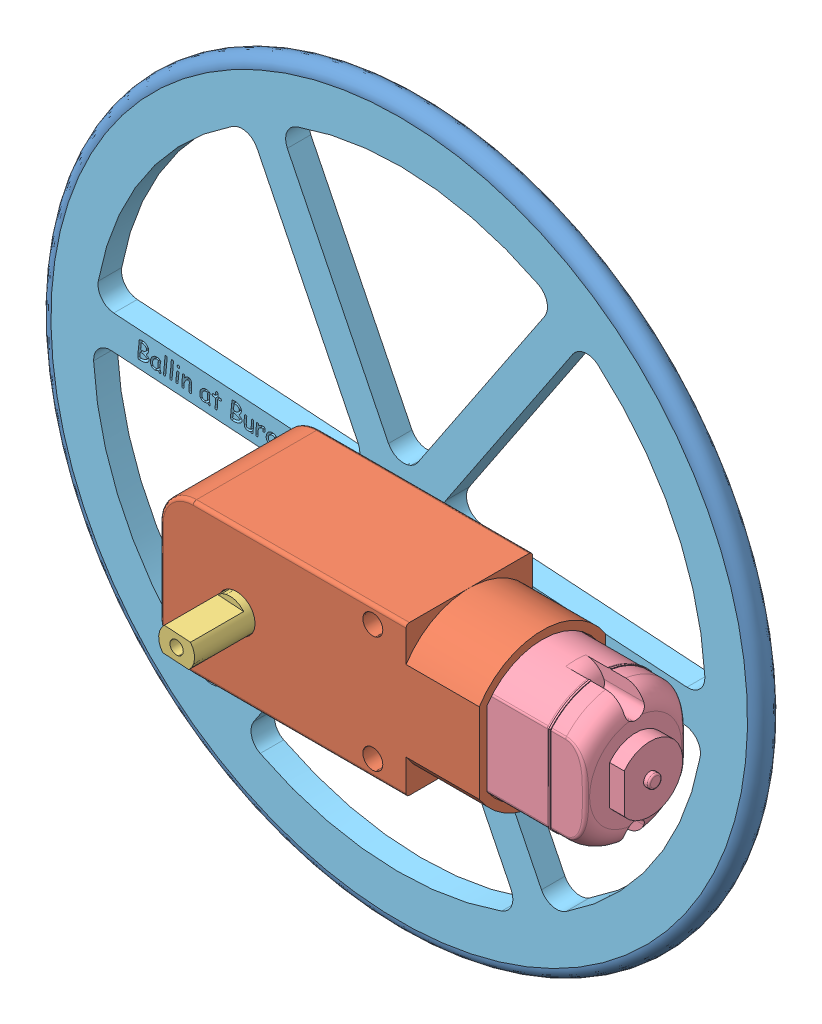
SolidWorks assembly roboty boi, configuration Default. Lengths in mm.
Overall size (115.08 115.08 37).
6 component instances, 5 part files, 6 mates.
Components (placement in the parent):
- 9452K192_Oil-Resistant Buna-N O-Ring-1: 9452K192_Oil-Resistant Buna-N O-Ring [9452K192] at (-19.8118 -11.25 -25.2165) x (0.997873 -0.065186 0) z (0 0 1) size (108.25 108.25 3.53)
- DC Motor Gearbox-1: DC Motor Gearbox [Default] at (28.5803 -42.486 -27.9985) x (0 0 1) z (-1 0 0) size (37 22.5 70)
  - Gearbox-1: Gearbox [Default] at (19.5167 31.236 22.8921) size (19 22.5 53)
  - output shaft-1: output shaft [Default] at (19.5167 31.236 48.3921) x (1 0 0) z (0 -0.997873 0.065186) size (37 5.4 5.4)
  - motor-1: motor [Default] at (19.5167 31.236 -2.1079) size (17.2 19.92 37.8)
- wheel-1: wheel [Default] at (-138.7417 -162.9407 -37.2208) x (0.997873 -0.065186 0) z (0 0 1) size (104.72 104.72 3.53)
Mates (geometry in assembly coordinates):
- Coincident8: coincident aligned: plane of 9452K192_Oil-Resistant Buna-N O-Ring-1 through (-19.8118 -11.25 -25.2165) normal (0 0 1); plane of wheel-1 through (-212.2604 -22.1089 -25.2165) normal (0 0 1)
- Coincident9: coincident anti-aligned: plane of 9452K192_Oil-Resistant Buna-N O-Ring-1 through (-19.8118 -11.25 -25.2165) normal (0.792403 0.609998 0); plane of wheel-1 through (-86.1728 74.9545 -37.2208) normal (-0.792403 -0.609998 0)
- Coincident10: coincident aligned: plane of 9452K192_Oil-Resistant Buna-N O-Ring-1 through (-19.8118 -11.25 -25.2165) normal (0.609998 -0.792403 0); plane of wheel-1 through (-145.8995 -108.3134 -37.2208) normal (0.609998 -0.792403 0)
- Concentric2: concentric anti-aligned: circle of DC Motor Gearbox-1/output shaft-1; circle of wheel-1
- Coincident11: coincident aligned: plane of DC Motor Gearbox-1/output shaft-1 through (-19.8118 -11.25 -26.9818) normal (0 0 -1); plane of wheel-1 through (-19.8118 -11.25 -26.9818) normal (0 0 -1)
- Coincident12: coincident anti-aligned: plane of DC Motor Gearbox-1/output shaft-1 through (-21.6536 -9.2757 -18.9818) normal (0.065186 0.997873 0); plane of wheel-1 through (-17.7288 -9.5321 -82.0335) normal (-0.065186 -0.997873 0)
